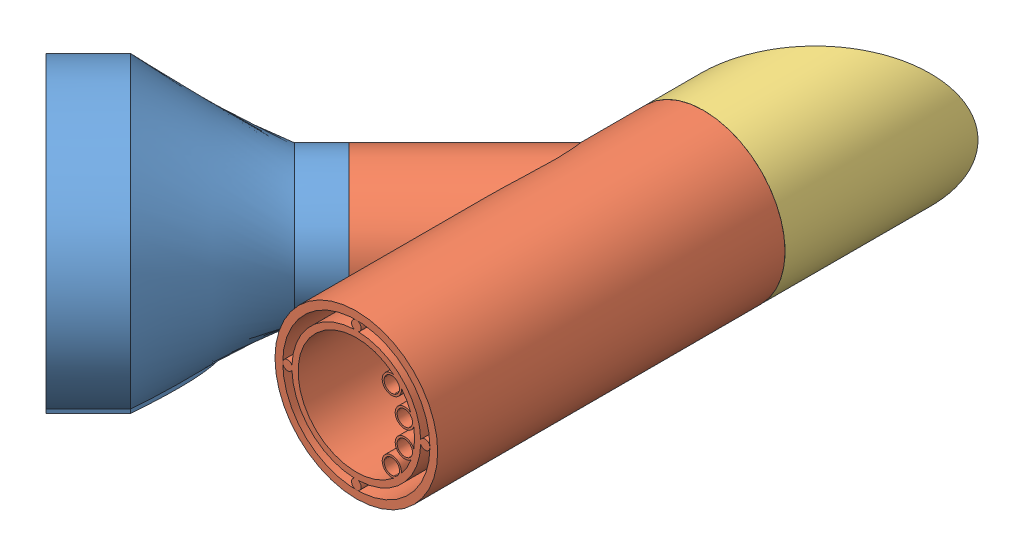
SolidWorks assembly Assem Short Length C Flat Half 1, configuration Default. Lengths in mm.
Overall size (123.01 56.64 166.05).
3 component instances, 3 part files, 5 mates.
Components (placement in the parent):
- Fan Bell C Flat-1: Fan Bell C Flat [Default] at (-158.0897 -29.7353 30.0617) x (0 1 0) z (-0.707107 0 -0.707107) size (56.64 55.5 67.27)
- Sensor Unit Straws Angled Condensed-1: Sensor Unit Straws Angled Condensed [Default] at (-90.9043 -30.2725 -51.2454) x (-1 0 0) z (0 0 -1) size (71.79 42.16 90)
- Double-Walled Pipe 0.05m with Dowels-2: Double-Walled Pipe 0.05m with Dowels [Default] at (-90.9043 -30.2725 -51.2454) x (-1 0 0) z (0 0 1) size (42.16 42.16 50)
Mates (geometry in assembly coordinates):
- Coincident4: coincident anti-aligned: circle of Fan Bell-1; circle of Sensor Unit Straws Angled-1
- Parallel7: parallel anti-aligned: plane of Fan Bell C Flat-1 through (-144.9825 -52.7353 67.3281) normal (0 -1 0)
- Concentric3: concentric anti-aligned: cylinder of Sensor Unit Straws Angled Condensed-1 through (-90.9043 -30.2725 89.0675) axis (0 0 -1) radius 15.1; cylinder of Double-Walled Pipe 0.05m with Dowels-2 through (-90.9043 -30.2725 -101.2454) axis (0 0 1) radius 15.1
- Perpendicular2: perpendicular: plane of Fan Bell C Flat-1 through (-169.0498 -29.7353 91.3347) normal (-0.707107 0 0.707107); plane of Double-Walled Pipe 0.05m with Dowels-2 through (-69.8243 46.2275 -101.2454) normal (-0.707107 0 -0.707107)
- Coincident7: coincident anti-aligned: plane of Sensor Unit Straws Angled Condensed-1 through (-90.9043 -30.2725 -51.2454) normal (0 0 -1); plane of Double-Walled Pipe 0.05m with Dowels-2 through (-90.9043 -30.2725 -51.2454) normal (0 0 1)
